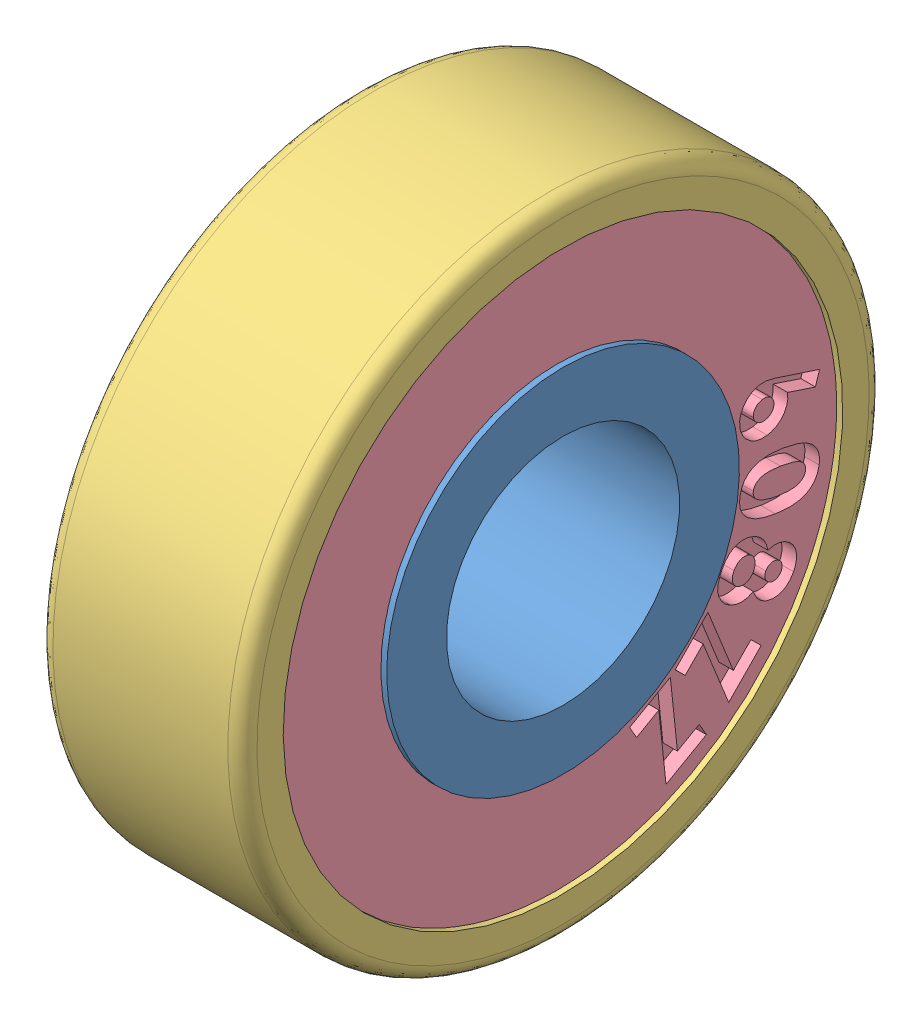
SolidWorks assembly 608ZZ Bearing, configuration Default. Lengths in mm.
Overall size (7 27.67 27.67).
16 component instances, 4 part files, 7 mates.
Components (placement in the parent):
- 608ZZ Inner-1: 608ZZ Inner [Default] at (3.036 7.0559 9.5653) size (7 12.1 12.1)
- Ball 3.969mm-1: Ball 3.969mm [Default] at (3.036 1.1223 14.6282) x (-0.963106 0.155967 0.219319) z (-0.14487 0.386335 -0.910911) size (3.97 3.97 3.97)
- Ball 3.969mm-2: Ball 3.969mm [Default] at (3.036 -0.6142 10.9831) x (-0.963106 0.025412 0.26792) z (-0.14487 0.790031 -0.595704) size (3.97 3.97 3.97)
- Ball 3.969mm-3: Ball 3.969mm [Default] at (3.036 -0.2955 6.9581) x (-0.963106 -0.111952 0.244731) z (-0.14487 0.982039 -0.12088) size (3.97 3.97 3.97)
- Ball 3.969mm-4: Ball 3.969mm [Default] at (3.036 1.993 3.6317) x (-0.963106 -0.219319 0.155967) z (-0.14487 0.910911 0.386335) size (3.97 3.97 3.97)
- Ball 3.969mm-5: Ball 3.969mm [Default] at (3.036 5.6381 1.8953) x (-0.963106 -0.26792 0.025412) z (-0.14487 0.595704 0.790031) size (3.97 3.97 3.97)
- Ball 3.969mm-6: Ball 3.969mm [Default] at (3.036 9.6631 2.214) x (-0.963106 -0.244731 -0.111952) z (-0.14487 0.12088 0.982039) size (3.97 3.97 3.97)
- Ball 3.969mm-7: Ball 3.969mm [Default] at (3.036 12.9895 4.5025) x (-0.963106 -0.155967 -0.219319) z (-0.14487 -0.386335 0.910911) size (3.97 3.97 3.97)
- Ball 3.969mm-8: Ball 3.969mm [Default] at (3.036 14.726 8.1476) x (-0.963106 -0.025412 -0.26792) z (-0.14487 -0.790031 0.595704) size (3.97 3.97 3.97)
- Ball 3.969mm-9: Ball 3.969mm [Default] at (3.036 14.4072 12.1726) x (-0.963106 0.111952 -0.244731) z (-0.14487 -0.982039 0.12088) size (3.97 3.97 3.97)
- Ball 3.969mm-10: Ball 3.969mm [Default] at (3.036 12.1187 15.4989) x (-0.963106 0.219319 -0.155967) z (-0.14487 -0.910911 -0.386335) size (3.97 3.97 3.97)
- Ball 3.969mm-11: Ball 3.969mm [Default] at (3.036 8.4736 17.2354) x (-0.963106 0.26792 -0.025412) z (-0.14487 -0.595704 -0.790031) size (3.97 3.97 3.97)
- Ball 3.969mm-12: Ball 3.969mm [Default] at (3.036 4.4487 16.9167) x (-0.963106 0.244731 0.111952) z (-0.14487 -0.12088 -0.982039) size (3.97 3.97 3.97)
- 608ZZ Outter-1: 608ZZ Outter [Default] at (3.036 7.0559 9.5653) x (1 0 0) z (0 0.952267 -0.305267) size (7 22 22)
- Bearing Sheild-1: Bearing Sheild [Default] at (5.336 7.0559 9.5653) x (0 0.927563 0.373668) z (1 0 0) size (19.2 19.2 1)
- Bearing Sheild-2: Bearing Sheild [Default] at (0.736 7.0559 9.5653) x (0 0 1) z (-1 0 0) size (19.2 19.2 1)
Mates (geometry in assembly coordinates):
- Coincident2: coincident: circle of 608ZZ Inner-1; point of Ball 3.969mm-1
- Concentric1: concentric aligned: circle of 608ZZ Inner-1; circle of 608ZZ Outter-1
- Coincident3: coincident anti-aligned: plane of 608ZZ Inner-1 through (-0.464 7.0559 9.5653) normal (-1 0 0); circle of 608ZZ Outter-1
- Coincident6: coincident aligned: cylinder of 608ZZ Outter-1 through (26.6962 7.0559 9.5653) axis (1 0 0) radius 9.6; circle of Bearing Sheild-1
- Distance2: distance = 0.2 mm aligned: plane of 608ZZ Outter-1 through (-0.464 7.0559 9.5653) normal (-1 0 0); plane of Bearing Sheild-2 through (-0.264 7.0559 9.5653) normal (-1 0 0)
- Concentric2: concentric anti-aligned: circle of 608ZZ Outter-1; circle of Bearing Sheild-2
- Distance3: distance = 0.2 mm aligned: plane of Bearing Sheild-1 through (6.336 7.0559 9.5653) normal (1 0 0); plane of 608ZZ Outter-1 through (6.536 7.0559 9.5653) normal (1 0 0)
